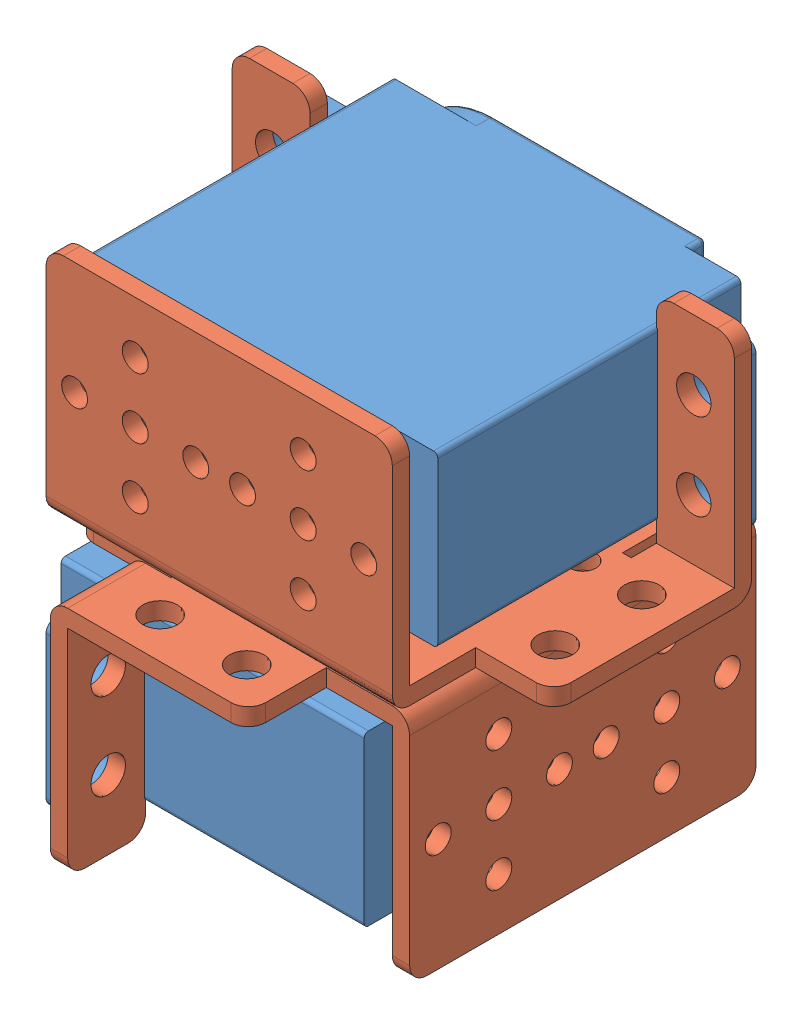
SolidWorks assembly 六足舵机装配图（正装）, configuration 默认. Lengths in mm.
Overall size (58 54 58).
6 component instances, 2 part files, 3 mates.
Components (placement in the parent):
- 舵机与支架装配图（正装）-1: 舵机与支架装配图（正装） [默认] at (10.121 -0.5657 -3.7238) size (58 27 48.1)
  - MG995舵机-1: MG995舵机 [默认] at (-17.2384 9.9205 0) size (54 19.5 43)
  - 舵机支架-1: 舵机支架 [默认] at (-5.7243 -13.1161 19.35) x (1 0 0) z (0 1 0) size (58 39.5 27)
- 舵机与支架装配图（正装）-2: 舵机与支架装配图（正装） [默认] at (-14.7033 -26.7979 21.1004) x (0 0 1) z (1 0 0) size (58 27 48.1)
  - MG995舵机-1: MG995舵机 [默认] at (-17.2384 9.9205 0) size (54 19.5 43)
  - 舵机支架-1: 舵机支架 [默认] at (-5.7243 -13.1161 19.35) x (1 0 0) z (0 1 0) size (58 39.5 27)
Mates (geometry in assembly coordinates):
- 距离1: distance = 0 mm anti-aligned: plane of 舵机与支架装配图（正装）-2/舵机支架-1 through (13.7709 -13.6818 -11.6238) normal (0 1 0); plane of 舵机与支架装配图（正装）-1/舵机支架-1 through (-22.6033 -13.6818 24.7503) normal (0 -1 0)
- 同心4: concentric aligned: circle of 舵机与支架装配图（正装）-1/舵机支架-1; cylinder of 舵机与支架装配图（正装）-2/舵机支架-1 through (0.8967 -15.6818 11.8762) axis (0 1 0) radius 1.5
- 同心5: concentric anti-aligned: circle of 舵机与支架装配图（正装）-1/舵机支架-1; circle of 舵机与支架装配图（正装）-2/舵机支架-1
